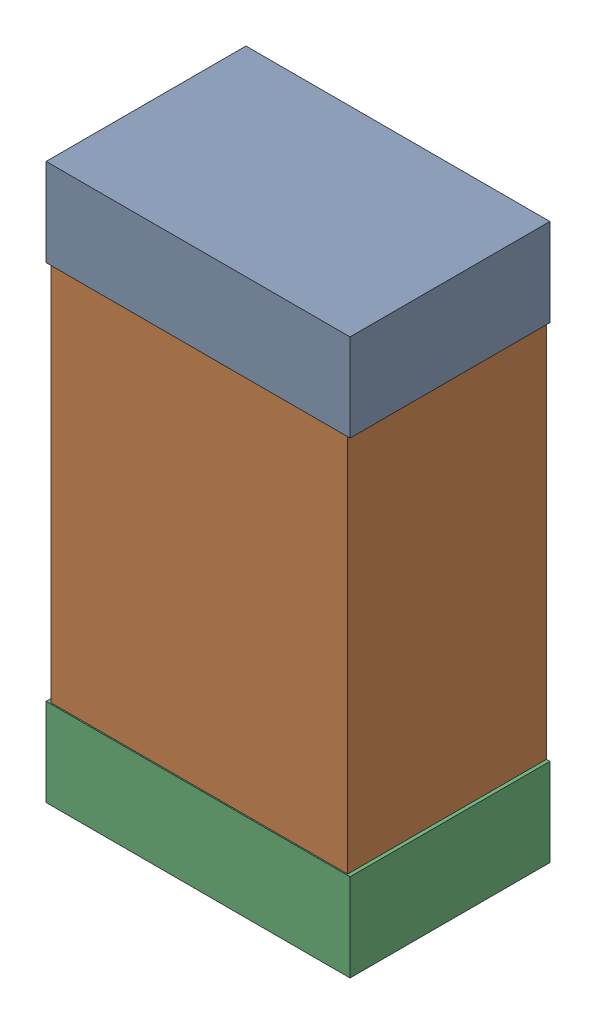
SolidWorks assembly 10uFKanaloa_v2.0.0_Power_1, configuration Default. Lengths in mm.
Overall size (1.3 2.38 0.85).
6 component instances, 2 part files, 0 mates.
Components (placement in the parent):
- 330415056-1: 330415056 [Default] at (142.8888 100.2104 0) size (1.3 0.38 0.85)
  - Extruded_2-1: Extruded_2 [Default] at origin size (1.3 0.38 0.85)
- 334787376-1: 334787376 [Default] at (142.8888 99.2104 0) size (1.27 2.2 0.85)
  - Extruded_16-1: Extruded_16 [Default] at origin size (1.27 2.2 0.85)
- 330415056-2: 330415056 [Default] at (142.8888 98.2104 0) size (1.3 0.38 0.85)
  - Extruded_2-1: Extruded_2 [Default] at origin size (1.3 0.38 0.85)
